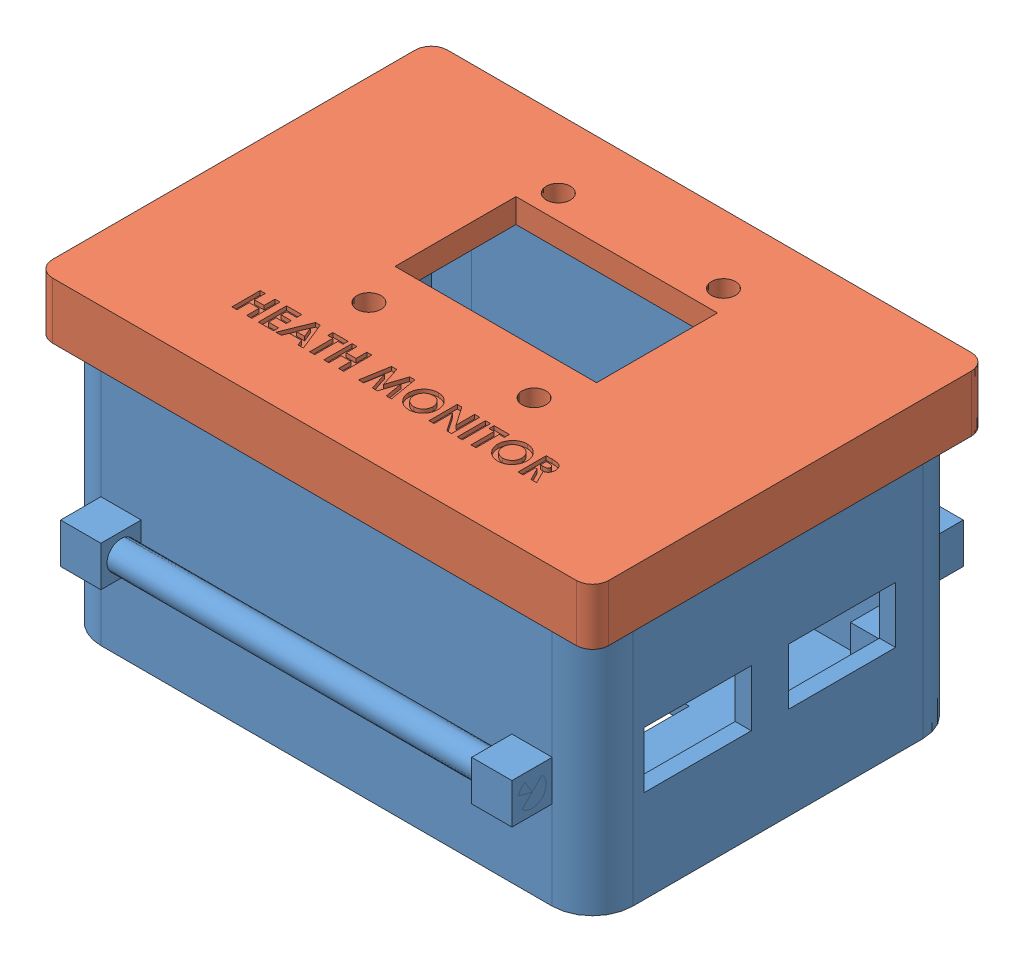
SolidWorks assembly heathmoniter, configuration Default. Lengths in mm.
Overall size (69 38 56).
3 component instances, 3 part files, 6 mates.
Components (placement in the parent):
- dongho-1: dongho [Default] at (-9.161 19.6932 72.8918) size (66 35 56)
- nap-1: nap [Default] at (-10.661 54.6932 74.3918) size (69 7 49)
- napday-1: napday [Default] at (-8.161 37.1932 52.8918) x (0 0 -1) z (0 1 0) size (21 5 12.5)
Mates (geometry in assembly coordinates):
- Coincident6: coincident: plane of dongho-1 through (56.839 54.6932 67.8918) normal (1 0 0); plane of nap-1 through (56.839 50.6932 67.8918) normal (-1 0 0)
- Coincident7: coincident: plane of dongho-1 through (-9.161 50.6932 67.8918) normal (-1 0 0); plane of nap-1 through (-9.161 50.6932 67.8918) normal (1 0 0)
- Coincident8: coincident: plane of dongho-1 through (-4.161 54.6932 72.8918) normal (0 0 1); plane of nap-1 through (-4.161 50.6932 72.8918) normal (0 0 -1)
- Coincident9: coincident: plane of dongho-1 through (-8.161 19.6932 72.8918) normal (-1 0 0); plane of napday-1 through (-8.161 37.1932 52.8918) normal (1 0 0)
- Coincident10: coincident: plane of dongho-1 through (0.839 40.6932 43.8918) normal (0 0 1); plane of napday-1 through (-5.161 37.1932 43.8918) normal (0 0 -1)
- Coincident11: coincident: plane of dongho-1 through (0.839 42.1932 45.3918) normal (0 -1 0); plane of napday-1 through (-5.161 42.1932 52.8918) normal (0 1 0)
